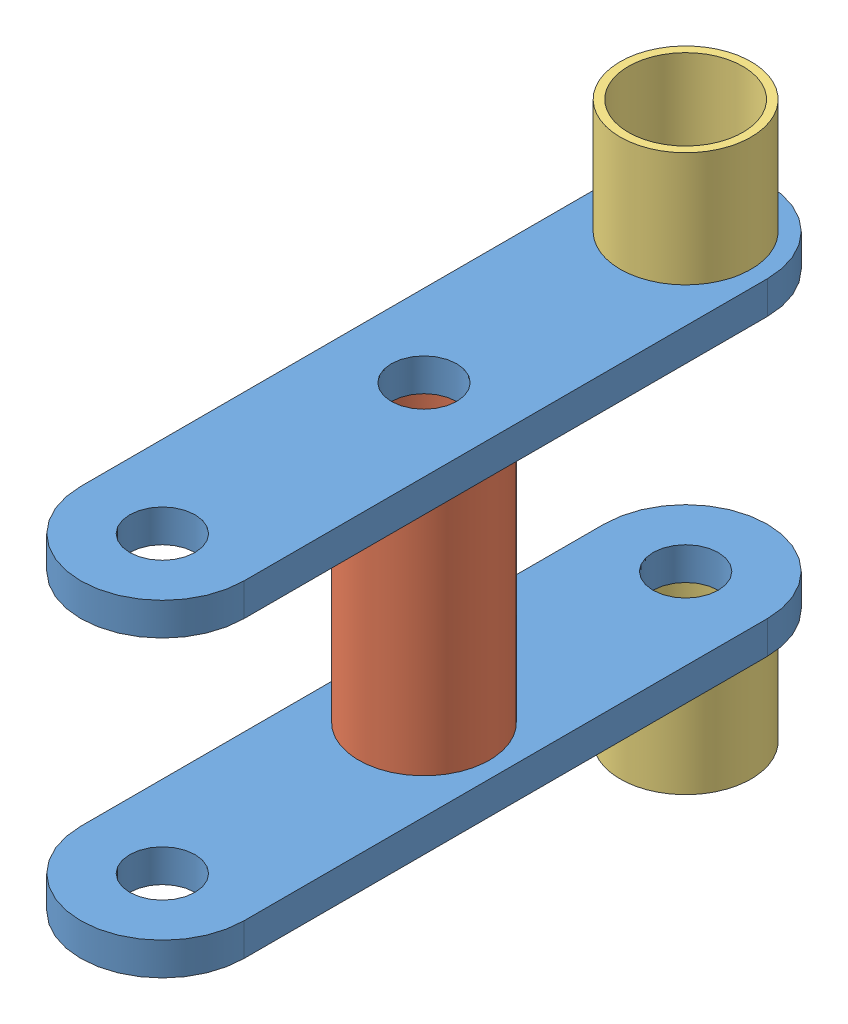
SolidWorks assembly bellcrank, configuration Default. Lengths in mm.
Overall size (15.88 53.97 66.67).
5 component instances, 3 part files, 8 mates.
Components (placement in the parent):
- bellcrank bar-1: bellcrank bar [Default] at (-99.275 3.7208 74.1797) size (15.88 3.17 66.67)
- bellcrank cyl-1: bellcrank cyl [Default] at (-99.275 32.2958 48.7797) x (1 0 0) z (0 -1 0) size (12.7 12.7 25.4)
- bellcrank bar-2: bellcrank bar [Default] at (-99.275 35.4708 74.1797) x (-1 0 0) z (0 0 1) size (15.88 3.17 66.67)
- bellcrank spacer-1: bellcrank spacer [Default] at (-99.275 35.4708 23.3797) x (0.974327 0 0.225138) z (0 1 0) size (12.7 12.7 11.11)
- bellcrank spacer-2: bellcrank spacer [Default] at (-99.275 -7.3917 23.3797) x (1 0 0) z (0 1 0) size (12.7 12.7 11.11)
Mates (geometry in assembly coordinates):
- Concentric1: concentric anti-aligned: cylinder of bellcrank bar-1 through (-99.275 6.8958 48.7797) axis (0 -1 0) radius 3.175; cylinder of bellcrank cyl-1 through (-99.275 6.8958 48.7797) axis (0 1 0) radius 5.5563
- Coincident1: coincident anti-aligned: plane of bellcrank bar-1 through (-99.275 6.8958 74.1797) normal (0 1 0); plane of bellcrank cyl-1 through (-99.275 6.8958 48.7797) normal (0 -1 0)
- Concentric3: concentric aligned: cylinder of bellcrank bar-2 through (-99.275 32.2958 48.7797) axis (0 1 0) radius 3.175; cylinder of bellcrank cyl-1 through (-99.275 6.8958 48.7797) axis (0 1 0) radius 5.5563
- Coincident3: coincident anti-aligned: plane of bellcrank cyl-1 through (-99.275 32.2958 48.7797) normal (0 1 0); plane of bellcrank bar-2 through (-99.275 32.2958 74.1797) normal (0 -1 0)
- Concentric8: concentric anti-aligned: cylinder of bellcrank bar-2 through (-99.275 32.2958 23.3797) axis (0 1 0) radius 3.175; cylinder of bellcrank spacer-1 through (-99.275 46.5833 23.3797) axis (0 -1 0) radius 5.5563
- Coincident8: coincident anti-aligned: plane of bellcrank bar-2 through (-99.275 35.4708 74.1797) normal (0 1 0); plane of bellcrank spacer-1 through (-99.275 35.4708 23.3797) normal (0 -1 0)
- Coincident9: coincident anti-aligned: plane of bellcrank bar-1 through (-99.275 3.7208 74.1797) normal (0 -1 0); plane of bellcrank spacer-2 through (-99.275 3.7208 23.3797) normal (0 1 0)
- Concentric9: concentric aligned: cylinder of bellcrank bar-1 through (-99.275 6.8958 23.3797) axis (0 -1 0) radius 3.175; cylinder of bellcrank spacer-2 through (-99.275 3.7208 23.3797) axis (0 -1 0) radius 5.5563
